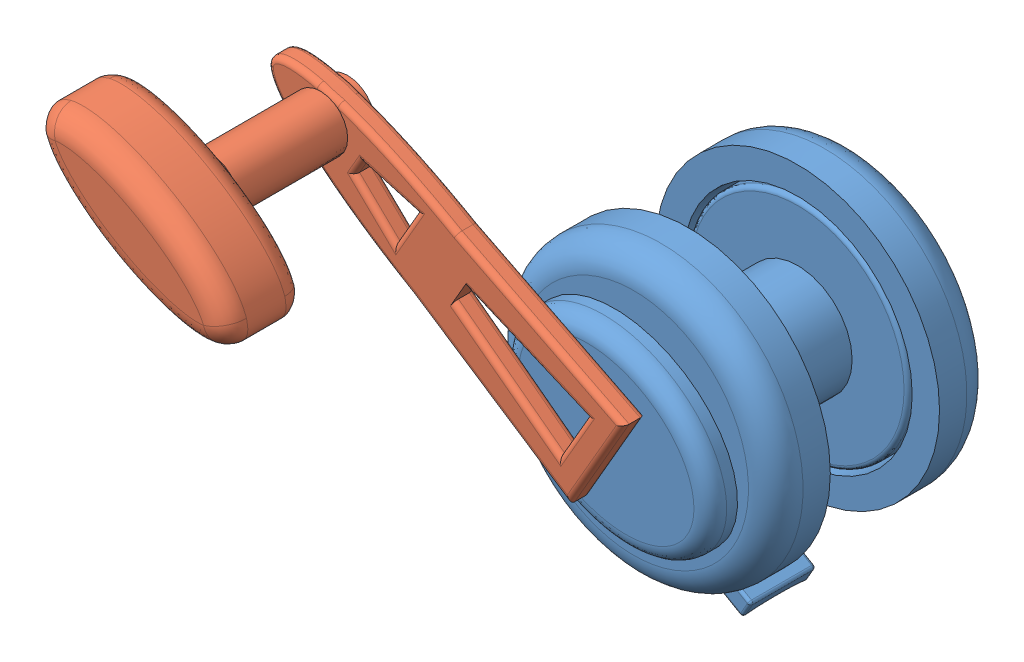
SolidWorks assembly GomexusReel, configuration Default. Lengths in mm.
Overall size (123.31 104.88 114.31).
2 component instances, 2 part files, 4 mates.
Components (placement in the parent):
- Reel-1: Reel [Default] at (56.1708 30.691 80.5169) x (-1 0 0) z (0 0 -1) size (75.82 77.87 64.77)
- Handle-1: Handle [Default] at (-5.2834 66.1753 117.3469) x (0.866025 -0.5 0) z (0 0 1) size (99.56 27.35 51.78)
Mates (geometry in assembly coordinates):
- Perpendicular2: perpendicular: plane of Handle-1 through (58.9347 29.099 86.8669) normal (0.866025 -0.5 0); plane of Reel-1 through (40.9324 4.2973 80.5169) normal (0.5 0.866025 0)
- Coincident4: coincident anti-aligned: plane of Reel-1 through (56.1708 30.691 86.8669) normal (0 0 1); plane of Handle-1 through (-5.2834 66.1753 86.8669) normal (0 0 -1)
- Distance1: distance = 25.4 mm aligned: plane of Handle-1 through (58.9347 29.099 86.8669) normal (0.866025 -0.5 0); plane of Reel-1 through (63.1517 -14.3969 47.4969) normal (0.866025 -0.5 0)
- Distance6: distance = 17.78 mm: line of Handle-1 through (52.5847 18.1005 88.1369) axis (0 0 1); plane of Reel-1 through (40.9324 4.2973 80.5169) normal (0.5 0.866025 0)
